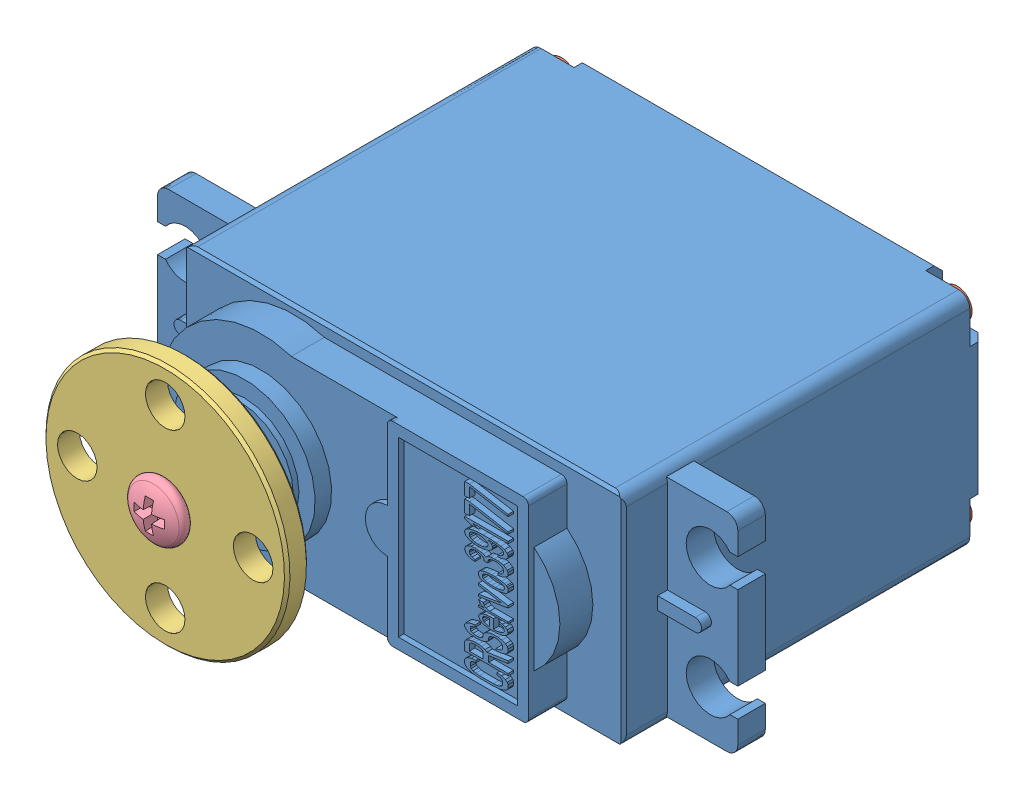
SolidWorks assembly Tetrix Servo CR (with Horn), configuration Default. Lengths in mm.
Overall size (52.8 22.2 46.43).
8 component instances, 4 part files, 0 mates.
Components (placement in the parent):
- Tetrix Servo Body-1: Tetrix Servo Body [Default] at origin size (52.8 20 41.4)
- Tetrix Servo Body Screw-1: Tetrix Servo Body Screw [Default] at (18 -8 -15) size (2.84 2.84 5.95)
- Tetrix Servo Body Screw-2: Tetrix Servo Body Screw [Default] at (18 8 -15) size (2.84 2.84 5.95)
- Tetrix Servo Body Screw-3: Tetrix Servo Body Screw [Default] at (-18 -8 -15) size (2.84 2.84 5.95)
- Tetrix Servo Body Screw-4: Tetrix Servo Body Screw [Default] at (-18 8 -15) size (2.84 2.84 5.95)
- Tetrix Servo Horn (with Screw)-1: Tetrix Servo Horn (with Screw) [Default] at (-10 0 22) x (-1 0 0) z (0 1 0) size (22.2 11.58 22.2)
  - Tetrix Servo Horn-1: Tetrix Servo Horn [Default] at origin size (22.2 6.2 22.2)
  - Tetrix Servo Screw-1: Tetrix Servo Screw [Default] at (0 -3.6552 0) size (5.25 11.58 5.25)
